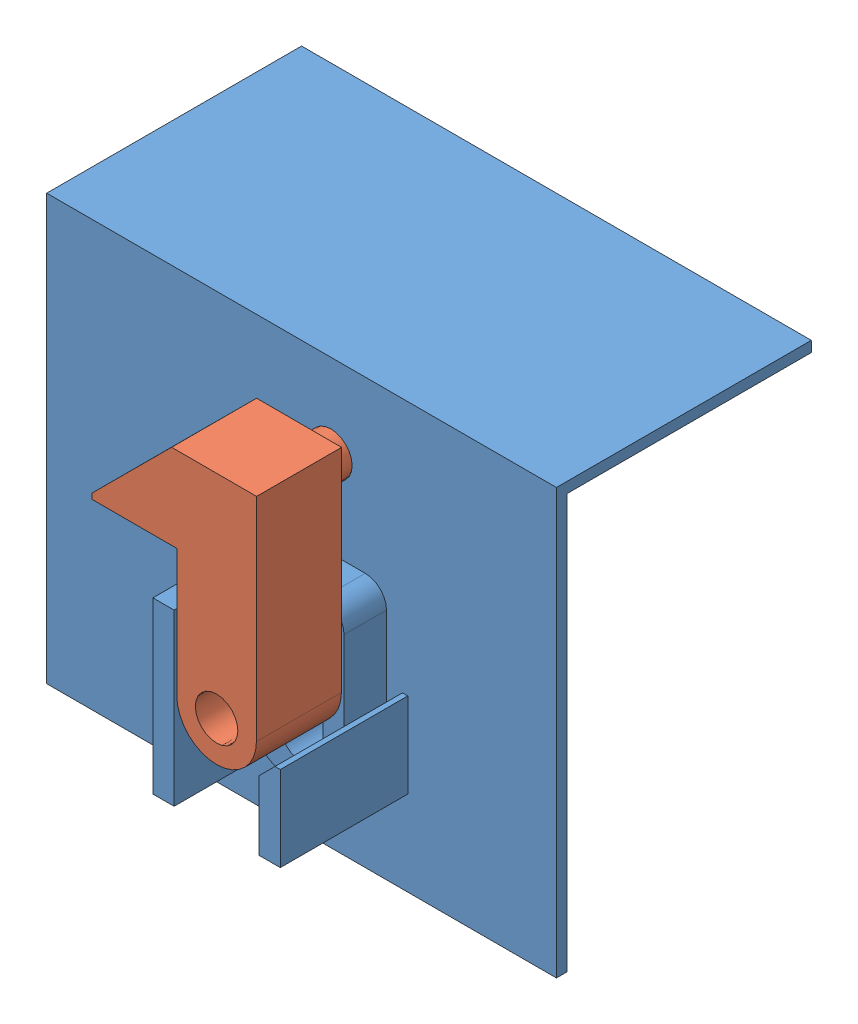
SolidWorks assembly Assem1, configuration Default. Lengths in mm.
Overall size (76.2 63.5 57.15).
2 component instances, 2 part files, 3 mates.
Components (placement in the parent):
- BAse-1: BAse [Default] at (-16.0476 29.7118 88.7976) size (76.2 63.5 57.15)
- hook-1: hook [Default] at (22.4493 56.9549 95.1476) x (1 -0.0008 0) z (0 0 1) size (24.61 37.7 17.46)
Mates (geometry in assembly coordinates):
- Tangent1: tangent anti-aligned: plane of BAse-1 through (25.2274 62.07 95.1476) normal (1 0 0); cylinder of hook-1 through (28.4024 56.9502 107.8476) axis (0 0 -1) radius 3.175
- Slot1: slot aligned: cylinder of hook-1 through (28.4024 56.9502 107.8476) axis (0 0 -1) radius 3.175; plane of BAse-1 through (25.2274 62.07 95.1476) normal (1 0 0); cylinder of BAse-1 through (28.4024 48.1536 95.1476) axis (0 0 -1) radius 3.175
- Coincident1: coincident anti-aligned: plane of BAse-1 through (31.5774 45.5868 95.1476) normal (0 0 1); plane of hook-1 through (28.4024 56.9502 95.1476) normal (0 0 -1)
